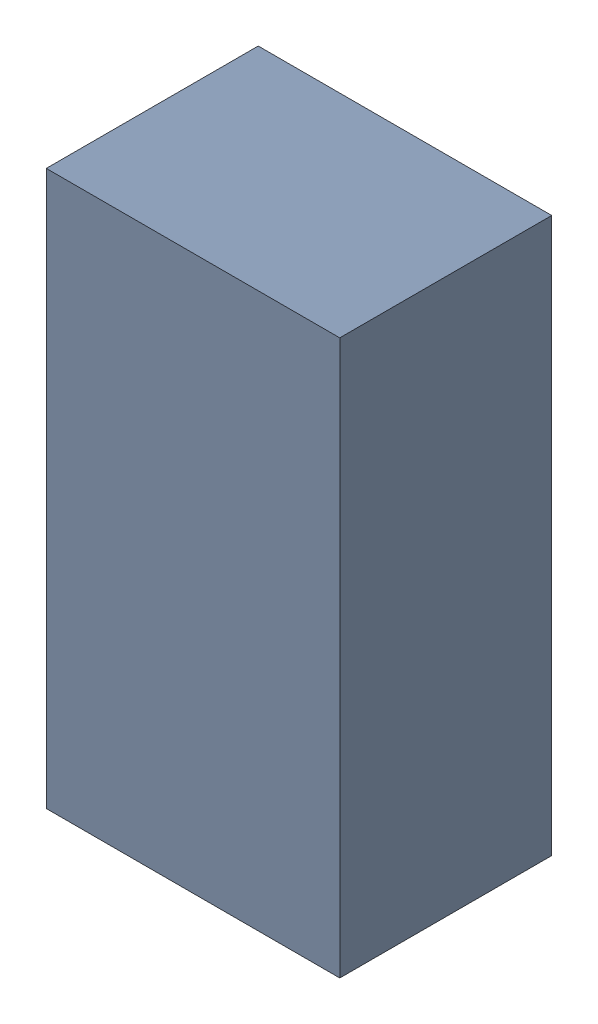
SolidWorks assembly C3, configuration Default. Lengths in mm.
Overall size (1.8 3.4 1.3).
2 component instances, 1 part files, 0 mates.
Components (placement in the parent):
- 5920131968-1: 5920131968 [Default] at (20.5 42.5 0) size (1.8 3.4 1.3)
  - Extruded_2-1: Extruded_2 [Default] at origin size (1.8 3.4 1.3)
